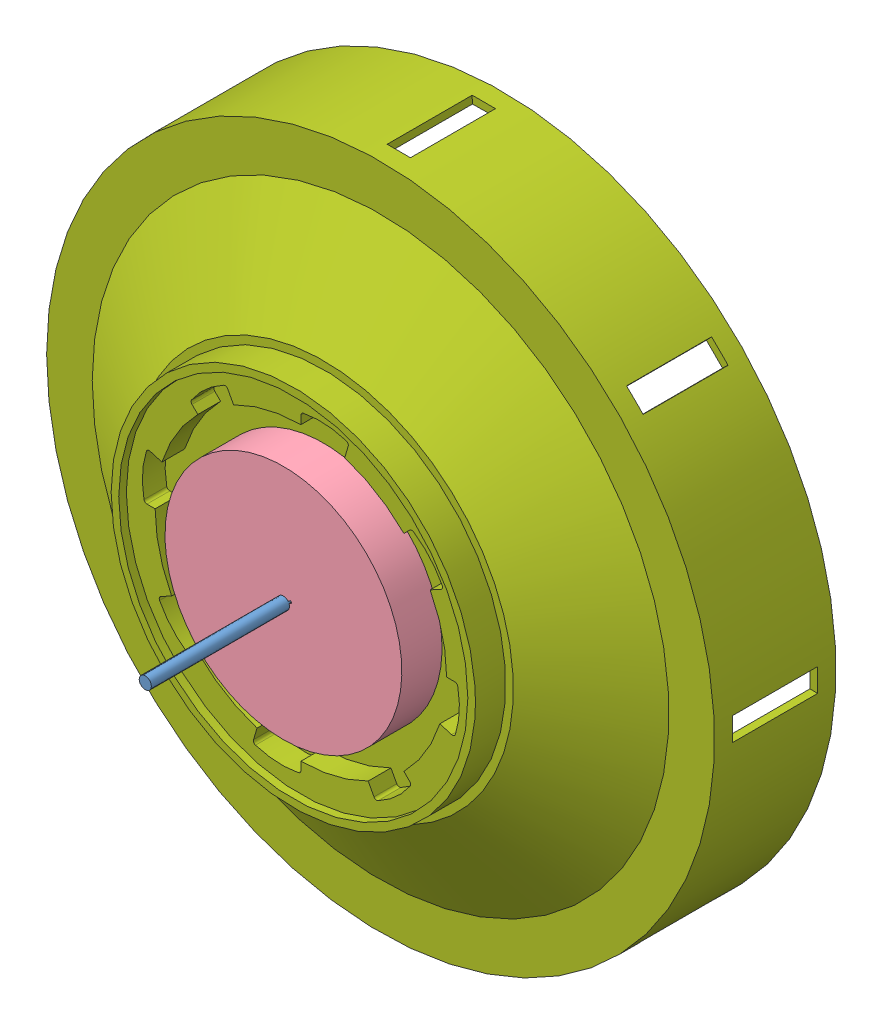
SolidWorks assembly osc_as, configuration Default. Lengths in mm.
Overall size (220 220 120).
9 component instances, 8 part files, 43 mates.
Components (placement in the parent):
- shaft-1: shaft [Default] x (0.998389 0.056733 0) z (0 0 1) size (4 4 60)
- internalBadassGear-1: internalBadassGear [Default] at (0 -27 0) x (-0.728898 -0.684623 0) z (0 0 1) size (20 19.78 12)
- rotationMonitor-1: rotationMonitor [Default] at (0 -27 -40) x (-0.728898 -0.684623 0) z (0 0 1) size (4 4 40)
- mfGear-1: mfGear [Default] x (-0.998389 -0.056733 0) z (0 0 1) size (78 78 14.5)
- internalBadassGear-2: internalBadassGear [Default] at (0 -27 -14.5) x (-0.728898 -0.684623 0) z (0 0 1) size (20 19.78 12)
- theOutputGear-1: theOutputGear [Default] at (0 0 -26.5) x (0 -1 0) z (0 0 1) size (29.87 29.87 12)
- theBadassCompoundGear-1: theBadassCompoundGear [Default] at (-14.7158 -14.9815 -2.5) x (-0.994997 0.099908 0) z (0 0 1) size (21.8 21.8 24)
- casing-1: casing [Default] x (-1 0 0) z (0 0 -1) size (220 220 68.75)
- shaft_op-1: shaft_op [Default] at (0 0 -30) x (-0.865931 -0.500163 0) z (0 0 -1) size (79 90.6 45.5)
Mates (geometry in assembly coordinates):
- Coincident1: coincident: circle of assembly; plane of assembly; plane of assembly; plane of shaft-1 through (0 0 0) normal (0 0 -1)
- Concentric1: concentric: cylinder of assembly; cylinder of shaft-1 through (0 0 60) axis (0 0 -1) radius 2; circle of assembly
- Coincident3: coincident: plane of ? through (0 0 0) normal (0 0 -1); plane of assembly through (0 0 0) normal (0 0 1)
- Concentric2: concentric: cylinder of assembly through (0 0 60) axis (0 0 -1) radius 2; cylinder of ? through (0 0 -38.0001) axis (0 0 1) radius 2
- Concentric3: concentric: cylinder of assembly; cylinder of internalBadassGear-1 through (0 -27 -38.0001) axis (0 0 1) radius 2; circle of assembly
- Coincident6: coincident: plane of ? through (0 -27 0) normal (0 0 -1); plane of assembly through (0 0 0) normal (0 0 1)
- Concentric4: concentric: cylinder of ? through (0 -27 -38.0001) axis (0 0 1) radius 2; cylinder of ? through (0 -27 0) axis (0 0 1) radius 2
- Coincident7: coincident: line of ? through (-10.8766 0 -27) axis (0 0.973301 0.229531); unknown of ?
- Concentric5: concentric: cylinder of assembly; cylinder of assembly; cylinder of internalBadassGear-1 through (0 -27 -38.0001) axis (0 0 1) radius 2; cylinder of rotationMonitor-1 through (0 -27 0) axis (0 0 -1) radius 2
- Perpendicular1: perpendicular: plane of assembly; plane of assembly; plane of internalBadassGear-1 through (0 -27 0) normal (0.684623 -0.728898 0); plane of rotationMonitor-1 through (0 -27 -40) normal (-0.728898 -0.684623 0)
- Coincident10: coincident: plane of assembly through (0 0 0) normal (0 0 1); plane of rotationMonitor-1 through (0 -27 0) normal (0 0 1); plane of assembly
- Coincident11: coincident: plane of assembly through (0 0 0) normal (0 0 1); plane of mfGear-1 through (0 0 0) normal (0 0 -1); plane of assembly
- Concentric6: concentric: cylinder of assembly; cylinder of assembly; cylinder of shaft-1 through (0 0 60) axis (0 0 -1) radius 2; cylinder of mfGear-1 through (0 0 14.5) axis (0 0 1) radius 2
- Concentric7: concentric: cylinder of ? through (0 0 -52.5001) axis (0 0 1) radius 2
- Distance1: distance = 2.5 mm: plane of ? through (0 0 0) normal (0 0 -1); plane of ? through (0 0 -2.5) normal (0 0 1)
- Coincident14: coincident: plane of ? through (0 0 -14.5) normal (0 0 -1); plane of ? through (0 -27 -14.5) normal (0 0 -1)
- Concentric8: concentric: cylinder of assembly; cylinder of assembly; cylinder of rotationMonitor-1 through (0 -27 0) axis (0 0 -1) radius 2; cylinder of internalBadassGear-2 through (0 -27 -52.5001) axis (0 0 1) radius 2
- Perpendicular2: perpendicular: plane of assembly; plane of assembly; plane of internalBadassGear-1 through (0 -27 0) normal (-0.728898 -0.684623 0); plane of internalBadassGear-2 through (0 -27 -14.5) normal (0.684623 -0.728898 0)
- GearMate1: gear = 2 : 1 mm: cylinder of ? through (0 -27 7.5) axis (0 0 1) radius 10; cylinder of ? through (0 0 7.5) axis (0 0 1) radius 19
- Coincident15: coincident: plane of ? through (0 0 -2.5) normal (0 0 1); plane of ? through (0 0 -2.5) normal (0 0 1)
- Concentric9: concentric: cylinder of ? through (0 0 -52.5001) axis (0 0 1) radius 2; cylinder of ? through (0 0 -2.5) axis (0 0 -1) radius 2
- Perpendicular3: perpendicular: plane of ? through (0 0 -14.5) normal (-0.074222 0.997242 0); unknown of ?
- Coincident17: coincident: plane of assembly; plane of assembly; plane of internalBadassGear-1 through (0 -27 0) normal (0 0 -1); plane of mfGear-1 through (1.9857 -34.9436 0) normal (0 0 -1)
- Concentric10: concentric: cylinder of ? through (0 0 -14.5) axis (0 0 -1) radius 2; cylinder of casing-1 through (0 0 -2.5) axis (0 0 1) radius 50
- Angle1: planar angle = 1.570796 rad: plane of casing-1 through (0 0 0) normal (0 1 0); plane of assembly through (0 0 0) normal (1 0 0)
- Coincident18: coincident: plane of casing-1 through (0 0 0) normal (0 0 1); plane of assembly through (0 0 0) normal (0 0 1)
- Coincident19: coincident: plane of assembly; plane of assembly; plane of shaft-1 through (0 0 0) normal (-0.056733 0.998389 0); plane of mfGear-1 through (0 0 0) normal (0.056733 -0.998389 0)
- Concentric11: concentric: circle of casing-1; cylinder of theOutputGear-1 through (0 0 -64.5001) axis (0 0 1) radius 2
- Coincident20: coincident: plane of assembly; plane of assembly; plane of internalBadassGear-2 through (0 -27 -14.5) normal (0 0 -1); plane of theBadassCompoundGear-1 through (-14.7158 -14.9815 -14.5) normal (0 0 -1)
- Concentric12: concentric: cylinder of casing-1 through (-14.7158 -14.9815 -10) axis (0 0 1) radius 2; cylinder of theBadassCompoundGear-1 through (-14.7158 -14.9815 -64.5001) axis (0 0 1) radius 2
- Coincident21: coincident: plane of assembly; plane of assembly; plane of theOutputGear-1 through (0 0 -26.5) normal (0 0 -1); plane of theBadassCompoundGear-1 through (-14.7158 -14.9815 -26.5) normal (0 0 -1)
- Coincident22: coincident: plane of ? through (0 0 -14.5) normal (0 0 1); plane of ? through (0 0 -14.5) normal (0 0 1)
- Concentric13: concentric: cylinder of ? through (0 0 -64.5001) axis (0 0 1) radius 2; cylinder of ? through (0 0 -14.5) axis (0 0 -1) radius 2
- GearMate2: gear = 20 : 18 mm: circle of assembly; circle of assembly; circle of internalBadassGear-2; circle of theBadassCompoundGear-1
- GearMate3: gear = 28 : 14 mm: circle of assembly; circle of assembly; circle of theBadassCompoundGear-1; circle of theOutputGear-1
- GearMate4: gear = 36 : 18 mm: circle of assembly; circle of assembly; circle of internalBadassGear-2; circle of mfGear-1
- Coincident26: coincident: unknown of ?; plane of ? through (0 0 -34.5) normal (0.99996 0.008932 0)
- Distance2: distance = 1.25 mm: plane of casing-1 through (0 0 0) normal (0 0 1); plane of ? through (0 0 -1.25) normal (0 0 1)
- Concentric14: concentric: cylinder of casing-1 through (0 0 -2.5) axis (0 0 1) radius 2; cylinder of ? through (0 0 -1.25) axis (0 0 -1) radius 2
- Slot1: slot: cylinder of ? through (0 36 -1.25) axis (0 0 -1) radius 2; cylinder of casing-1 through (0 0 -2.5) axis (0 0 1) radius 38; cylinder of ? through (0 0 -1.25) axis (0 0 -1) radius 2; cylinder of casing-1 through (0 36 -2.5) axis (0 0 1) radius 2
- Perpendicular4: perpendicular: plane of theOutputGear-1 through (0 0 -26.5) normal (0 -1 0); plane of ? through (0 0 -31.25) normal (1 0 0)
- Concentric16: concentric: cylinder of assembly; cylinder of assembly; cylinder of rotationMonitor-1 through (0 -27 0) axis (0 0 -1) radius 2; cylinder of casing-1 through (0 -27 1.25) axis (0 0 1) radius 2
- Concentric17: concentric: cylinder of casing-1 through (0 0 1.25) axis (0 0 1) radius 2; cylinder of shaft_op-1 through (0 0 -14.5) axis (0 0 -1) radius 2
